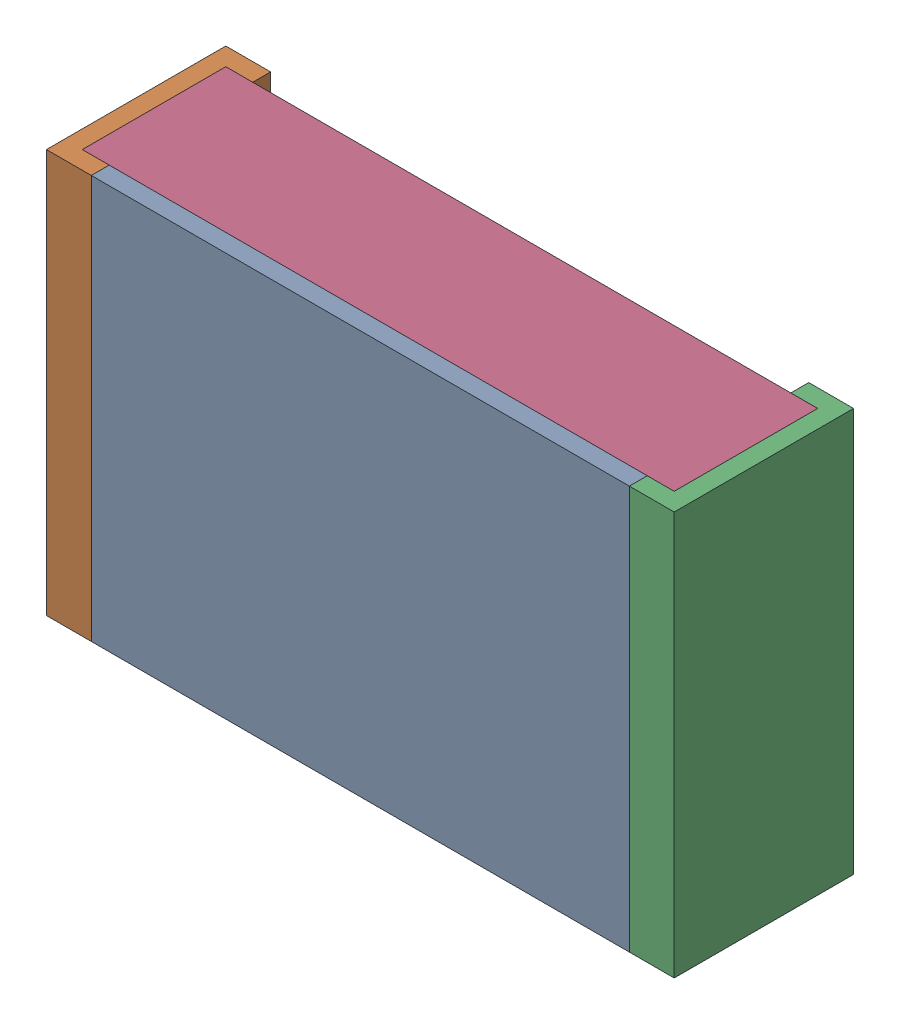
SolidWorks assembly R104, configuration По умолчанию. Lengths in mm.
Overall size (2.1 1.35 0.6).
5 component instances, 3 part files, 0 mates.
Components (placement in the parent):
- RESC2012X06N.step-4-1: RESC2012X06N.step-4 [По умолчанию] at origin size (2.1 1.35 0.6)
  - RESC2012X06N.step-Part-1-1: RESC2012X06N.step-Part-1 [По умолчанию] at (-0.9 -0.675 0.54) size (1.8 1.35 0.06)
  - RESC2012X06N.step-Part-2-1: RESC2012X06N.step-Part-2 [По умолчанию] at (-1.05 -0.675 0) size (0.15 1.35 0.6)
  - RESC2012X06N.step-Part-2-2: RESC2012X06N.step-Part-2 [По умолчанию] at (1.05 0.675 0) x (-1 0 0) z (0 0 1) size (0.15 1.35 0.6)
  - RESC2012X06N.step-Part-3-1: RESC2012X06N.step-Part-3 [По умолчанию] at (-1.05 -0.675 0) size (1.98 1.35 0.48)
